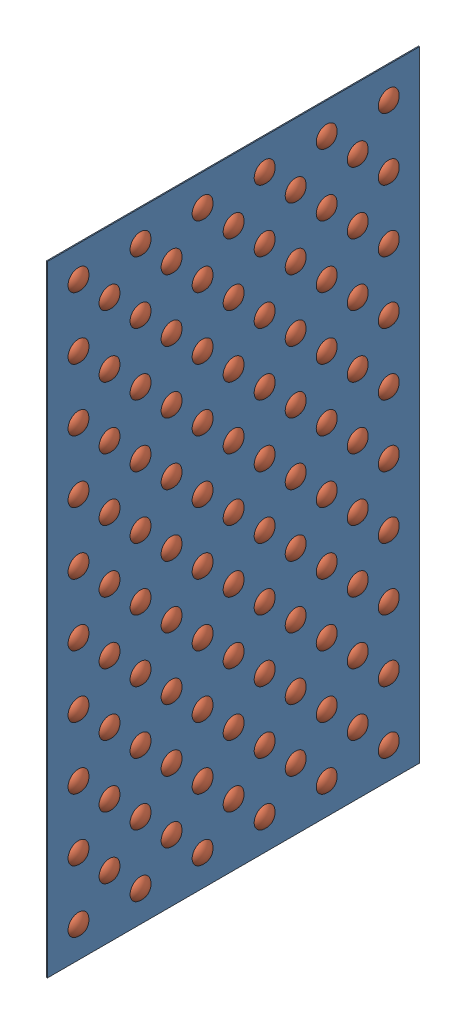
SolidWorks assembly Rough Terrain Assembly 2.0, configuration Default. Lengths in mm.
Overall size (15.24 1524 914.4).
106 component instances, 2 part files, 4 mates.
Components (placement in the parent):
- Plywood Floor 2.0-1: Plywood Floor 2.0 [Default] at (-31.6665 931.7281 1394.0117) size (2.54 1524 914.4)
- Terrain obstacle 2.0 8-11-2019-108: Terrain obstacle 2.0 8-11-2019 [Default] at (-29.1265 245.9281 1775.0117) x (0 0.141825 0.989892) z (0 0.989892 -0.141825) size (50.8 12.7 50.8)
- Terrain obstacle 2.0 8-11-2019-112: Terrain obstacle 2.0 8-11-2019 [Default] at (-29.1265 322.1281 1698.8117) x (0 0.141825 0.989892) z (0 0.989892 -0.141825) size (50.8 12.7 50.8)
- Terrain obstacle 2.0 8-11-2019-113: Terrain obstacle 2.0 8-11-2019 [Default] at (-29.1265 398.3281 1775.0117) x (0 0.141825 0.989892) z (0 0.989892 -0.141825) size (50.8 12.7 50.8)
- Terrain obstacle 2.0 8-11-2019-114: Terrain obstacle 2.0 8-11-2019 [Default] at (-29.1265 550.7281 1775.0117) x (0 0.141825 0.989892) z (0 0.989892 -0.141825) size (50.8 12.7 50.8)
- Terrain obstacle 2.0 8-11-2019-115: Terrain obstacle 2.0 8-11-2019 [Default] at (-29.1265 703.1281 1775.0117) x (0 0.141825 0.989892) z (0 0.989892 -0.141825) size (50.8 12.7 50.8)
- Terrain obstacle 2.0 8-11-2019-116: Terrain obstacle 2.0 8-11-2019 [Default] at (-29.1265 855.5281 1775.0117) x (0 0.141825 0.989892) z (0 0.989892 -0.141825) size (50.8 12.7 50.8)
- Terrain obstacle 2.0 8-11-2019-117: Terrain obstacle 2.0 8-11-2019 [Default] at (-29.1265 1007.9281 1775.0117) x (0 0.141825 0.989892) z (0 0.989892 -0.141825) size (50.8 12.7 50.8)
- Terrain obstacle 2.0 8-11-2019-118: Terrain obstacle 2.0 8-11-2019 [Default] at (-29.1265 1160.3281 1775.0117) x (0 0.141825 0.989892) z (0 0.989892 -0.141825) size (50.8 12.7 50.8)
- Terrain obstacle 2.0 8-11-2019-119: Terrain obstacle 2.0 8-11-2019 [Default] at (-29.1265 1312.7281 1775.0117) x (0 0.141825 0.989892) z (0 0.989892 -0.141825) size (50.8 12.7 50.8)
- Terrain obstacle 2.0 8-11-2019-120: Terrain obstacle 2.0 8-11-2019 [Default] at (-29.1265 1465.1281 1775.0117) x (0 0.141825 0.989892) z (0 0.989892 -0.141825) size (50.8 12.7 50.8)
- Terrain obstacle 2.0 8-11-2019-121: Terrain obstacle 2.0 8-11-2019 [Default] at (-29.1265 1617.5281 1775.0117) x (0 0.141825 0.989892) z (0 0.989892 -0.141825) size (50.8 12.7 50.8)
- Terrain obstacle 2.0 8-11-2019-624: Terrain obstacle 2.0 8-11-2019 [Default] at (-29.1265 245.9281 1622.6117) x (0 0.141825 0.989892) z (0 0.989892 -0.141825) size (50.8 12.7 50.8)
- Terrain obstacle 2.0 8-11-2019-625: Terrain obstacle 2.0 8-11-2019 [Default] at (-29.1265 245.9281 1470.2117) x (0 0.141825 0.989892) z (0 0.989892 -0.141825) size (50.8 12.7 50.8)
- Terrain obstacle 2.0 8-11-2019-626: Terrain obstacle 2.0 8-11-2019 [Default] at (-29.1265 245.9281 1317.8117) x (0 0.141825 0.989892) z (0 0.989892 -0.141825) size (50.8 12.7 50.8)
- Terrain obstacle 2.0 8-11-2019-627: Terrain obstacle 2.0 8-11-2019 [Default] at (-29.1265 245.9281 1165.4117) x (0 0.141825 0.989892) z (0 0.989892 -0.141825) size (50.8 12.7 50.8)
- Terrain obstacle 2.0 8-11-2019-628: Terrain obstacle 2.0 8-11-2019 [Default] at (-29.1265 245.9281 1013.0117) x (0 0.141825 0.989892) z (0 0.989892 -0.141825) size (50.8 12.7 50.8)
- Terrain obstacle 2.0 8-11-2019-629: Terrain obstacle 2.0 8-11-2019 [Default] at (-29.1265 398.3281 1622.6117) x (0 0.141825 0.989892) z (0 0.989892 -0.141825) size (50.8 12.7 50.8)
- Terrain obstacle 2.0 8-11-2019-630: Terrain obstacle 2.0 8-11-2019 [Default] at (-29.1265 398.3281 1470.2117) x (0 0.141825 0.989892) z (0 0.989892 -0.141825) size (50.8 12.7 50.8)
- Terrain obstacle 2.0 8-11-2019-631: Terrain obstacle 2.0 8-11-2019 [Default] at (-29.1265 398.3281 1317.8117) x (0 0.141825 0.989892) z (0 0.989892 -0.141825) size (50.8 12.7 50.8)
- Terrain obstacle 2.0 8-11-2019-632: Terrain obstacle 2.0 8-11-2019 [Default] at (-29.1265 398.3281 1165.4117) x (0 0.141825 0.989892) z (0 0.989892 -0.141825) size (50.8 12.7 50.8)
- Terrain obstacle 2.0 8-11-2019-633: Terrain obstacle 2.0 8-11-2019 [Default] at (-29.1265 398.3281 1013.0117) x (0 0.141825 0.989892) z (0 0.989892 -0.141825) size (50.8 12.7 50.8)
- Terrain obstacle 2.0 8-11-2019-634: Terrain obstacle 2.0 8-11-2019 [Default] at (-29.1265 550.7281 1622.6117) x (0 0.141825 0.989892) z (0 0.989892 -0.141825) size (50.8 12.7 50.8)
- Terrain obstacle 2.0 8-11-2019-635: Terrain obstacle 2.0 8-11-2019 [Default] at (-29.1265 550.7281 1470.2117) x (0 0.141825 0.989892) z (0 0.989892 -0.141825) size (50.8 12.7 50.8)
- Terrain obstacle 2.0 8-11-2019-636: Terrain obstacle 2.0 8-11-2019 [Default] at (-29.1265 550.7281 1317.8117) x (0 0.141825 0.989892) z (0 0.989892 -0.141825) size (50.8 12.7 50.8)
- Terrain obstacle 2.0 8-11-2019-637: Terrain obstacle 2.0 8-11-2019 [Default] at (-29.1265 550.7281 1165.4117) x (0 0.141825 0.989892) z (0 0.989892 -0.141825) size (50.8 12.7 50.8)
- Terrain obstacle 2.0 8-11-2019-638: Terrain obstacle 2.0 8-11-2019 [Default] at (-29.1265 550.7281 1013.0117) x (0 0.141825 0.989892) z (0 0.989892 -0.141825) size (50.8 12.7 50.8)
- Terrain obstacle 2.0 8-11-2019-639: Terrain obstacle 2.0 8-11-2019 [Default] at (-29.1265 703.1281 1622.6117) x (0 0.141825 0.989892) z (0 0.989892 -0.141825) size (50.8 12.7 50.8)
- Terrain obstacle 2.0 8-11-2019-640: Terrain obstacle 2.0 8-11-2019 [Default] at (-29.1265 703.1281 1470.2117) x (0 0.141825 0.989892) z (0 0.989892 -0.141825) size (50.8 12.7 50.8)
- Terrain obstacle 2.0 8-11-2019-641: Terrain obstacle 2.0 8-11-2019 [Default] at (-29.1265 703.1281 1317.8117) x (0 0.141825 0.989892) z (0 0.989892 -0.141825) size (50.8 12.7 50.8)
- Terrain obstacle 2.0 8-11-2019-642: Terrain obstacle 2.0 8-11-2019 [Default] at (-29.1265 703.1281 1165.4117) x (0 0.141825 0.989892) z (0 0.989892 -0.141825) size (50.8 12.7 50.8)
- Terrain obstacle 2.0 8-11-2019-643: Terrain obstacle 2.0 8-11-2019 [Default] at (-29.1265 703.1281 1013.0117) x (0 0.141825 0.989892) z (0 0.989892 -0.141825) size (50.8 12.7 50.8)
- Terrain obstacle 2.0 8-11-2019-644: Terrain obstacle 2.0 8-11-2019 [Default] at (-29.1265 855.5281 1622.6117) x (0 0.141825 0.989892) z (0 0.989892 -0.141825) size (50.8 12.7 50.8)
- Terrain obstacle 2.0 8-11-2019-645: Terrain obstacle 2.0 8-11-2019 [Default] at (-29.1265 855.5281 1470.2117) x (0 0.141825 0.989892) z (0 0.989892 -0.141825) size (50.8 12.7 50.8)
- Terrain obstacle 2.0 8-11-2019-646: Terrain obstacle 2.0 8-11-2019 [Default] at (-29.1265 855.5281 1317.8117) x (0 0.141825 0.989892) z (0 0.989892 -0.141825) size (50.8 12.7 50.8)
- Terrain obstacle 2.0 8-11-2019-647: Terrain obstacle 2.0 8-11-2019 [Default] at (-29.1265 855.5281 1165.4117) x (0 0.141825 0.989892) z (0 0.989892 -0.141825) size (50.8 12.7 50.8)
- Terrain obstacle 2.0 8-11-2019-648: Terrain obstacle 2.0 8-11-2019 [Default] at (-29.1265 855.5281 1013.0117) x (0 0.141825 0.989892) z (0 0.989892 -0.141825) size (50.8 12.7 50.8)
- Terrain obstacle 2.0 8-11-2019-649: Terrain obstacle 2.0 8-11-2019 [Default] at (-29.1265 1007.9281 1622.6117) x (0 0.141825 0.989892) z (0 0.989892 -0.141825) size (50.8 12.7 50.8)
- Terrain obstacle 2.0 8-11-2019-650: Terrain obstacle 2.0 8-11-2019 [Default] at (-29.1265 1007.9281 1470.2117) x (0 0.141825 0.989892) z (0 0.989892 -0.141825) size (50.8 12.7 50.8)
- Terrain obstacle 2.0 8-11-2019-651: Terrain obstacle 2.0 8-11-2019 [Default] at (-29.1265 1007.9281 1317.8117) x (0 0.141825 0.989892) z (0 0.989892 -0.141825) size (50.8 12.7 50.8)
- Terrain obstacle 2.0 8-11-2019-652: Terrain obstacle 2.0 8-11-2019 [Default] at (-29.1265 1007.9281 1165.4117) x (0 0.141825 0.989892) z (0 0.989892 -0.141825) size (50.8 12.7 50.8)
- Terrain obstacle 2.0 8-11-2019-653: Terrain obstacle 2.0 8-11-2019 [Default] at (-29.1265 1007.9281 1013.0117) x (0 0.141825 0.989892) z (0 0.989892 -0.141825) size (50.8 12.7 50.8)
- Terrain obstacle 2.0 8-11-2019-654: Terrain obstacle 2.0 8-11-2019 [Default] at (-29.1265 1160.3281 1622.6117) x (0 0.141825 0.989892) z (0 0.989892 -0.141825) size (50.8 12.7 50.8)
- Terrain obstacle 2.0 8-11-2019-655: Terrain obstacle 2.0 8-11-2019 [Default] at (-29.1265 1160.3281 1470.2117) x (0 0.141825 0.989892) z (0 0.989892 -0.141825) size (50.8 12.7 50.8)
- Terrain obstacle 2.0 8-11-2019-656: Terrain obstacle 2.0 8-11-2019 [Default] at (-29.1265 1160.3281 1317.8117) x (0 0.141825 0.989892) z (0 0.989892 -0.141825) size (50.8 12.7 50.8)
- Terrain obstacle 2.0 8-11-2019-657: Terrain obstacle 2.0 8-11-2019 [Default] at (-29.1265 1160.3281 1165.4117) x (0 0.141825 0.989892) z (0 0.989892 -0.141825) size (50.8 12.7 50.8)
- Terrain obstacle 2.0 8-11-2019-658: Terrain obstacle 2.0 8-11-2019 [Default] at (-29.1265 1160.3281 1013.0117) x (0 0.141825 0.989892) z (0 0.989892 -0.141825) size (50.8 12.7 50.8)
- Terrain obstacle 2.0 8-11-2019-659: Terrain obstacle 2.0 8-11-2019 [Default] at (-29.1265 1312.7281 1622.6117) x (0 0.141825 0.989892) z (0 0.989892 -0.141825) size (50.8 12.7 50.8)
- Terrain obstacle 2.0 8-11-2019-660: Terrain obstacle 2.0 8-11-2019 [Default] at (-29.1265 1312.7281 1470.2117) x (0 0.141825 0.989892) z (0 0.989892 -0.141825) size (50.8 12.7 50.8)
- Terrain obstacle 2.0 8-11-2019-661: Terrain obstacle 2.0 8-11-2019 [Default] at (-29.1265 1312.7281 1317.8117) x (0 0.141825 0.989892) z (0 0.989892 -0.141825) size (50.8 12.7 50.8)
- Terrain obstacle 2.0 8-11-2019-662: Terrain obstacle 2.0 8-11-2019 [Default] at (-29.1265 1312.7281 1165.4117) x (0 0.141825 0.989892) z (0 0.989892 -0.141825) size (50.8 12.7 50.8)
- Terrain obstacle 2.0 8-11-2019-663: Terrain obstacle 2.0 8-11-2019 [Default] at (-29.1265 1312.7281 1013.0117) x (0 0.141825 0.989892) z (0 0.989892 -0.141825) size (50.8 12.7 50.8)
- Terrain obstacle 2.0 8-11-2019-664: Terrain obstacle 2.0 8-11-2019 [Default] at (-29.1265 1465.1281 1622.6117) x (0 0.141825 0.989892) z (0 0.989892 -0.141825) size (50.8 12.7 50.8)
- Terrain obstacle 2.0 8-11-2019-665: Terrain obstacle 2.0 8-11-2019 [Default] at (-29.1265 1465.1281 1470.2117) x (0 0.141825 0.989892) z (0 0.989892 -0.141825) size (50.8 12.7 50.8)
- Terrain obstacle 2.0 8-11-2019-666: Terrain obstacle 2.0 8-11-2019 [Default] at (-29.1265 1465.1281 1317.8117) x (0 0.141825 0.989892) z (0 0.989892 -0.141825) size (50.8 12.7 50.8)
- Terrain obstacle 2.0 8-11-2019-667: Terrain obstacle 2.0 8-11-2019 [Default] at (-29.1265 1465.1281 1165.4117) x (0 0.141825 0.989892) z (0 0.989892 -0.141825) size (50.8 12.7 50.8)
- Terrain obstacle 2.0 8-11-2019-668: Terrain obstacle 2.0 8-11-2019 [Default] at (-29.1265 1465.1281 1013.0117) x (0 0.141825 0.989892) z (0 0.989892 -0.141825) size (50.8 12.7 50.8)
- Terrain obstacle 2.0 8-11-2019-669: Terrain obstacle 2.0 8-11-2019 [Default] at (-29.1265 1617.5281 1622.6117) x (0 0.141825 0.989892) z (0 0.989892 -0.141825) size (50.8 12.7 50.8)
- Terrain obstacle 2.0 8-11-2019-670: Terrain obstacle 2.0 8-11-2019 [Default] at (-29.1265 1617.5281 1470.2117) x (0 0.141825 0.989892) z (0 0.989892 -0.141825) size (50.8 12.7 50.8)
- Terrain obstacle 2.0 8-11-2019-671: Terrain obstacle 2.0 8-11-2019 [Default] at (-29.1265 1617.5281 1317.8117) x (0 0.141825 0.989892) z (0 0.989892 -0.141825) size (50.8 12.7 50.8)
- Terrain obstacle 2.0 8-11-2019-672: Terrain obstacle 2.0 8-11-2019 [Default] at (-29.1265 1617.5281 1165.4117) x (0 0.141825 0.989892) z (0 0.989892 -0.141825) size (50.8 12.7 50.8)
- Terrain obstacle 2.0 8-11-2019-673: Terrain obstacle 2.0 8-11-2019 [Default] at (-29.1265 1617.5281 1013.0117) x (0 0.141825 0.989892) z (0 0.989892 -0.141825) size (50.8 12.7 50.8)
- Terrain obstacle 2.0 8-11-2019-1124: Terrain obstacle 2.0 8-11-2019 [Default] at (-29.1265 322.1281 1546.4117) x (0 0.141825 0.989892) z (0 0.989892 -0.141825) size (50.8 12.7 50.8)
- Terrain obstacle 2.0 8-11-2019-1125: Terrain obstacle 2.0 8-11-2019 [Default] at (-29.1265 322.1281 1394.0117) x (0 0.141825 0.989892) z (0 0.989892 -0.141825) size (50.8 12.7 50.8)
- Terrain obstacle 2.0 8-11-2019-1126: Terrain obstacle 2.0 8-11-2019 [Default] at (-29.1265 322.1281 1241.6117) x (0 0.141825 0.989892) z (0 0.989892 -0.141825) size (50.8 12.7 50.8)
- Terrain obstacle 2.0 8-11-2019-1127: Terrain obstacle 2.0 8-11-2019 [Default] at (-29.1265 322.1281 1089.2117) x (0 0.141825 0.989892) z (0 0.989892 -0.141825) size (50.8 12.7 50.8)
- Terrain obstacle 2.0 8-11-2019-1128: Terrain obstacle 2.0 8-11-2019 [Default] at (-29.1265 474.5281 1698.8117) x (0 0.141825 0.989892) z (0 0.989892 -0.141825) size (50.8 12.7 50.8)
- Terrain obstacle 2.0 8-11-2019-1129: Terrain obstacle 2.0 8-11-2019 [Default] at (-29.1265 474.5281 1546.4117) x (0 0.141825 0.989892) z (0 0.989892 -0.141825) size (50.8 12.7 50.8)
- Terrain obstacle 2.0 8-11-2019-1130: Terrain obstacle 2.0 8-11-2019 [Default] at (-29.1265 474.5281 1394.0117) x (0 0.141825 0.989892) z (0 0.989892 -0.141825) size (50.8 12.7 50.8)
- Terrain obstacle 2.0 8-11-2019-1131: Terrain obstacle 2.0 8-11-2019 [Default] at (-29.1265 474.5281 1241.6117) x (0 0.141825 0.989892) z (0 0.989892 -0.141825) size (50.8 12.7 50.8)
- Terrain obstacle 2.0 8-11-2019-1132: Terrain obstacle 2.0 8-11-2019 [Default] at (-29.1265 474.5281 1089.2117) x (0 0.141825 0.989892) z (0 0.989892 -0.141825) size (50.8 12.7 50.8)
- Terrain obstacle 2.0 8-11-2019-1133: Terrain obstacle 2.0 8-11-2019 [Default] at (-29.1265 626.9281 1698.8117) x (0 0.141825 0.989892) z (0 0.989892 -0.141825) size (50.8 12.7 50.8)
- Terrain obstacle 2.0 8-11-2019-1134: Terrain obstacle 2.0 8-11-2019 [Default] at (-29.1265 626.9281 1546.4117) x (0 0.141825 0.989892) z (0 0.989892 -0.141825) size (50.8 12.7 50.8)
- Terrain obstacle 2.0 8-11-2019-1135: Terrain obstacle 2.0 8-11-2019 [Default] at (-29.1265 626.9281 1394.0117) x (0 0.141825 0.989892) z (0 0.989892 -0.141825) size (50.8 12.7 50.8)
- Terrain obstacle 2.0 8-11-2019-1136: Terrain obstacle 2.0 8-11-2019 [Default] at (-29.1265 626.9281 1241.6117) x (0 0.141825 0.989892) z (0 0.989892 -0.141825) size (50.8 12.7 50.8)
- Terrain obstacle 2.0 8-11-2019-1137: Terrain obstacle 2.0 8-11-2019 [Default] at (-29.1265 626.9281 1089.2117) x (0 0.141825 0.989892) z (0 0.989892 -0.141825) size (50.8 12.7 50.8)
- Terrain obstacle 2.0 8-11-2019-1138: Terrain obstacle 2.0 8-11-2019 [Default] at (-29.1265 779.3281 1698.8117) x (0 0.141825 0.989892) z (0 0.989892 -0.141825) size (50.8 12.7 50.8)
- Terrain obstacle 2.0 8-11-2019-1139: Terrain obstacle 2.0 8-11-2019 [Default] at (-29.1265 779.3281 1546.4117) x (0 0.141825 0.989892) z (0 0.989892 -0.141825) size (50.8 12.7 50.8)
- Terrain obstacle 2.0 8-11-2019-1140: Terrain obstacle 2.0 8-11-2019 [Default] at (-29.1265 779.3281 1394.0117) x (0 0.141825 0.989892) z (0 0.989892 -0.141825) size (50.8 12.7 50.8)
- Terrain obstacle 2.0 8-11-2019-1141: Terrain obstacle 2.0 8-11-2019 [Default] at (-29.1265 779.3281 1241.6117) x (0 0.141825 0.989892) z (0 0.989892 -0.141825) size (50.8 12.7 50.8)
- Terrain obstacle 2.0 8-11-2019-1142: Terrain obstacle 2.0 8-11-2019 [Default] at (-29.1265 779.3281 1089.2117) x (0 0.141825 0.989892) z (0 0.989892 -0.141825) size (50.8 12.7 50.8)
- Terrain obstacle 2.0 8-11-2019-1143: Terrain obstacle 2.0 8-11-2019 [Default] at (-29.1265 931.7281 1698.8117) x (0 0.141825 0.989892) z (0 0.989892 -0.141825) size (50.8 12.7 50.8)
- Terrain obstacle 2.0 8-11-2019-1144: Terrain obstacle 2.0 8-11-2019 [Default] at (-29.1265 931.7281 1546.4117) x (0 0.141825 0.989892) z (0 0.989892 -0.141825) size (50.8 12.7 50.8)
- Terrain obstacle 2.0 8-11-2019-1145: Terrain obstacle 2.0 8-11-2019 [Default] at (-29.1265 931.7281 1394.0117) x (0 0.141825 0.989892) z (0 0.989892 -0.141825) size (50.8 12.7 50.8)
- Terrain obstacle 2.0 8-11-2019-1146: Terrain obstacle 2.0 8-11-2019 [Default] at (-29.1265 931.7281 1241.6117) x (0 0.141825 0.989892) z (0 0.989892 -0.141825) size (50.8 12.7 50.8)
- Terrain obstacle 2.0 8-11-2019-1147: Terrain obstacle 2.0 8-11-2019 [Default] at (-29.1265 931.7281 1089.2117) x (0 0.141825 0.989892) z (0 0.989892 -0.141825) size (50.8 12.7 50.8)
- Terrain obstacle 2.0 8-11-2019-1148: Terrain obstacle 2.0 8-11-2019 [Default] at (-29.1265 1084.1281 1698.8117) x (0 0.141825 0.989892) z (0 0.989892 -0.141825) size (50.8 12.7 50.8)
- Terrain obstacle 2.0 8-11-2019-1149: Terrain obstacle 2.0 8-11-2019 [Default] at (-29.1265 1084.1281 1546.4117) x (0 0.141825 0.989892) z (0 0.989892 -0.141825) size (50.8 12.7 50.8)
- Terrain obstacle 2.0 8-11-2019-1150: Terrain obstacle 2.0 8-11-2019 [Default] at (-29.1265 1084.1281 1394.0117) x (0 0.141825 0.989892) z (0 0.989892 -0.141825) size (50.8 12.7 50.8)
- Terrain obstacle 2.0 8-11-2019-1151: Terrain obstacle 2.0 8-11-2019 [Default] at (-29.1265 1084.1281 1241.6117) x (0 0.141825 0.989892) z (0 0.989892 -0.141825) size (50.8 12.7 50.8)
- Terrain obstacle 2.0 8-11-2019-1152: Terrain obstacle 2.0 8-11-2019 [Default] at (-29.1265 1084.1281 1089.2117) x (0 0.141825 0.989892) z (0 0.989892 -0.141825) size (50.8 12.7 50.8)
- Terrain obstacle 2.0 8-11-2019-1153: Terrain obstacle 2.0 8-11-2019 [Default] at (-29.1265 1236.5281 1698.8117) x (0 0.141825 0.989892) z (0 0.989892 -0.141825) size (50.8 12.7 50.8)
- Terrain obstacle 2.0 8-11-2019-1154: Terrain obstacle 2.0 8-11-2019 [Default] at (-29.1265 1236.5281 1546.4117) x (0 0.141825 0.989892) z (0 0.989892 -0.141825) size (50.8 12.7 50.8)
- Terrain obstacle 2.0 8-11-2019-1155: Terrain obstacle 2.0 8-11-2019 [Default] at (-29.1265 1236.5281 1394.0117) x (0 0.141825 0.989892) z (0 0.989892 -0.141825) size (50.8 12.7 50.8)
- Terrain obstacle 2.0 8-11-2019-1156: Terrain obstacle 2.0 8-11-2019 [Default] at (-29.1265 1236.5281 1241.6117) x (0 0.141825 0.989892) z (0 0.989892 -0.141825) size (50.8 12.7 50.8)
- Terrain obstacle 2.0 8-11-2019-1157: Terrain obstacle 2.0 8-11-2019 [Default] at (-29.1265 1236.5281 1089.2117) x (0 0.141825 0.989892) z (0 0.989892 -0.141825) size (50.8 12.7 50.8)
- Terrain obstacle 2.0 8-11-2019-1158: Terrain obstacle 2.0 8-11-2019 [Default] at (-29.1265 1388.9281 1698.8117) x (0 0.141825 0.989892) z (0 0.989892 -0.141825) size (50.8 12.7 50.8)
- Terrain obstacle 2.0 8-11-2019-1159: Terrain obstacle 2.0 8-11-2019 [Default] at (-29.1265 1388.9281 1546.4117) x (0 0.141825 0.989892) z (0 0.989892 -0.141825) size (50.8 12.7 50.8)
- Terrain obstacle 2.0 8-11-2019-1160: Terrain obstacle 2.0 8-11-2019 [Default] at (-29.1265 1388.9281 1394.0117) x (0 0.141825 0.989892) z (0 0.989892 -0.141825) size (50.8 12.7 50.8)
- Terrain obstacle 2.0 8-11-2019-1161: Terrain obstacle 2.0 8-11-2019 [Default] at (-29.1265 1388.9281 1241.6117) x (0 0.141825 0.989892) z (0 0.989892 -0.141825) size (50.8 12.7 50.8)
- Terrain obstacle 2.0 8-11-2019-1162: Terrain obstacle 2.0 8-11-2019 [Default] at (-29.1265 1388.9281 1089.2117) x (0 0.141825 0.989892) z (0 0.989892 -0.141825) size (50.8 12.7 50.8)
- Terrain obstacle 2.0 8-11-2019-1163: Terrain obstacle 2.0 8-11-2019 [Default] at (-29.1265 1541.3281 1698.8117) x (0 0.141825 0.989892) z (0 0.989892 -0.141825) size (50.8 12.7 50.8)
- Terrain obstacle 2.0 8-11-2019-1164: Terrain obstacle 2.0 8-11-2019 [Default] at (-29.1265 1541.3281 1546.4117) x (0 0.141825 0.989892) z (0 0.989892 -0.141825) size (50.8 12.7 50.8)
- Terrain obstacle 2.0 8-11-2019-1165: Terrain obstacle 2.0 8-11-2019 [Default] at (-29.1265 1541.3281 1394.0117) x (0 0.141825 0.989892) z (0 0.989892 -0.141825) size (50.8 12.7 50.8)
- Terrain obstacle 2.0 8-11-2019-1166: Terrain obstacle 2.0 8-11-2019 [Default] at (-29.1265 1541.3281 1241.6117) x (0 0.141825 0.989892) z (0 0.989892 -0.141825) size (50.8 12.7 50.8)
- Terrain obstacle 2.0 8-11-2019-1167: Terrain obstacle 2.0 8-11-2019 [Default] at (-29.1265 1541.3281 1089.2117) x (0 0.141825 0.989892) z (0 0.989892 -0.141825) size (50.8 12.7 50.8)
Mates (geometry in assembly coordinates):
- Coincident1: coincident: circle of Plywood Floor 2.0-1; circle of ?
- Coincident2: coincident: circle of Plywood Floor 2.0-1; circle of ?
- Coincident3: coincident: circle of Plywood Floor 2.0-1; circle of Terrain obstacle 2.0 8-11-2019-108
- Coincident4: coincident: circle of Plywood Floor 2.0-1; circle of Terrain obstacle 2.0 8-11-2019-112
